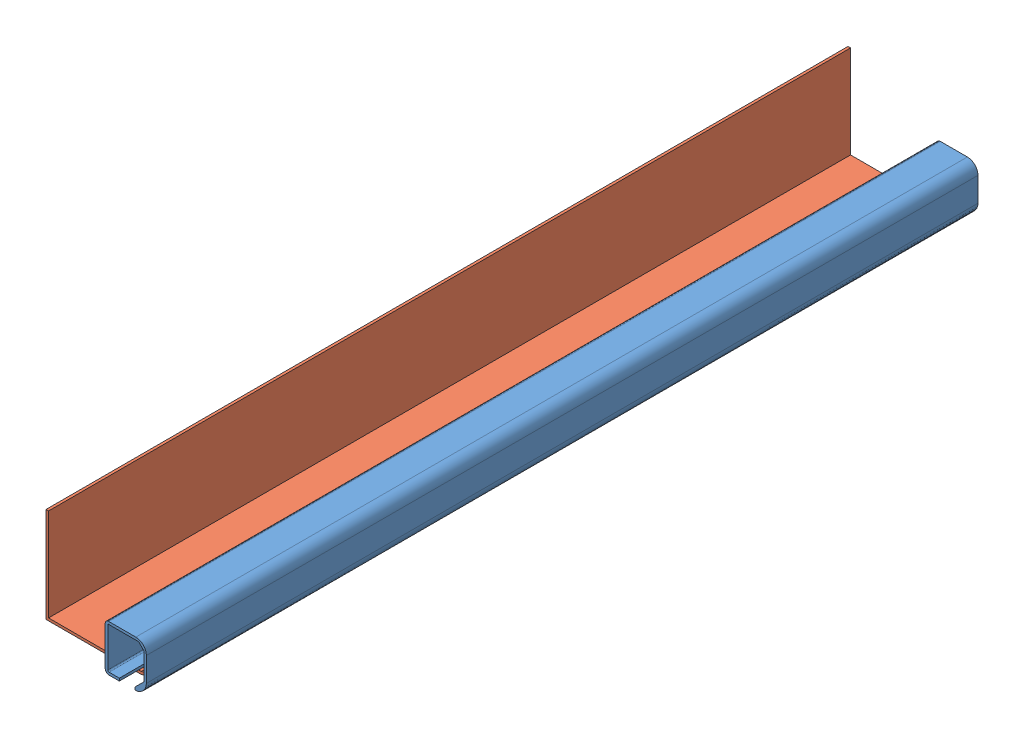
SolidWorks assembly Laufschienen, configuration Rechts. Lengths in mm.
Overall size (47.5 37 323).
2 component instances, 2 part files, 4 mates.
Components (placement in the parent):
- Laufschiene-Lade-1: Laufschiene-Lade [Default] at (61.6497 134.5373 88.3501) size (16 18 323)
- Laufschiene-Wand-1: Laufschiene-Wand [Default] at (42.1497 116.5373 402.8501) x (-1 0 0) z (0 0 -1) size (44.5 37 311.5)
Mates (geometry in assembly coordinates):
- LimitAbstand1: limit distance = 3 mm aligned: plane of Laufschiene-Lade-1 through (56.1497 119.0373 411.3501) normal (0 0 1); plane of Laufschiene-Wand-1 through (60.1497 118.5373 402.8501) normal (0 0 1)
- Abstand1: distance = 4.5 mm anti-aligned: plane of Laufschiene-Wand-1 through (57.6497 130.0373 91.3501) normal (0 1 0); plane of Laufschiene-Lade-1 through (55.6497 134.5373 411.3501) normal (0 -1 0)
- Abstand2: distance = 2 mm anti-aligned: plane of Laufschiene-Wand-1 through (67.6497 130.0373 91.3501) normal (1 0 0); plane of Laufschiene-Lade-1 through (69.6497 132.5373 411.3501) normal (-1 0 0)
- LimitAbstand2: limit distance = 3 mm aligned: plane of Laufschiene-Lade-1 through (56.1497 119.0373 88.3501) normal (0 0 -1); plane of Laufschiene-Wand-1 through (60.1497 118.5373 91.3501) normal (0 0 -1)
